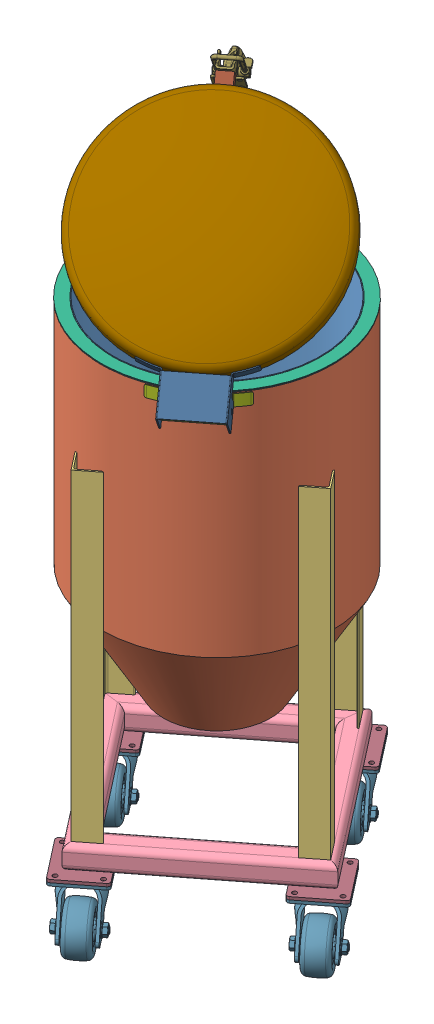
SolidWorks assembly Full Assembly, configuration Default. Lengths in mm.
Overall size (807.2 1692.42 807.2).
22 component instances, 14 part files, 40 mates.
Components (placement in the parent):
- Inner Tank (SUS304 Stainless)-1: Inner Tank (SUS304 Stainless) [Default] at origin size (460.38 751.55 460.38)
- Outer Tank (5052 Aluminum)-1: Outer Tank (5052 Aluminum) [Default] at (0 -53.975 0) size (510.43 744.74 510.43) (hidden)
- Legs^Full Assembly-1: Legs^Full Assembly [Default<As Machined>] at origin size (574.08 711.2 574.08) (virtual)
- Base Support^Full Assembly-1: Base Support^Full Assembly [Default<As Machined>] at origin size (609.73 50.8 609.73) (virtual)
- Part2^Full Assembly-1: Part2^Full Assembly [Default] at origin size (510.43 1.27 510.43) (virtual)
- Part1^Full Assembly-1: Part1^Full Assembly [Default] at origin size (511.18 1.59 511.18) (virtual)
- Aluminum Hinge Bottom-1: Aluminum Hinge Bottom [Default] at (181.4938 423.092 230.6241) x (0.788011 0 -0.615661) z (0.615661 0 0.788011) size (172.01 30.25 52.98)
- Aluminum Hinge Top-1: Aluminum Hinge Top [Default] at (181.4938 452.7347 230.6241) x (-0.788011 0 0.615661) z (0.615661 0 0.788011) size (104.78 30.94 44.15)
- Lid Assembly-1: Lid Assembly [Default] at (50.9024 635.7879 63.4747) x (-0.788011 0 0.615661) z (-0.464006 0.657251 -0.593901) size (548.2 438.64 642.51)
  - Lid-2: Lid [Default] at (211.2181 -60.2546 -11.3558) x (0.978448 -0.106422 -0.176957) z (0.118934 -0.410093 0.904256) size (467.18 231.16 437.78)
  - Stainless Hinge (Lid)-1: Stainless Hinge (Lid) [Default] at (0 31.628 -311.3405) x (-1 0 0) z (0 0 -1) size (198.67 69.73 99.8)
  - Part1-1: Part1 [Default] at origin size (30.23 25.4 22.84)
  - 5071A590-1: 5071A590 [Default] at (0.0381 -49.8475 255.0668) x (-1 0 0) z (0 1 0) size (60.86 76.1 227.53)
- 5071A590-1: 5071A590 [Default] at (-157.1255 407.035 -201.1115) x (0.788011 0 -0.615661) z (0 1 0) size (60.86 76.1 227.53)
- Caster Plate-1: Caster Plate [Default] at (36.7204 -517.525 -259.7516) x (0.614757 0 0.788716) z (-0.788716 0 0.614757) size (114.3 6.35 101.6)
- Caster Plate-3: Caster Plate [Default] at (-260.8562 -517.525 -27.8083) x (0.614757 0 0.788716) z (-0.788716 0 0.614757) size (114.3 6.35 101.6)
- Caster Plate-4: Caster Plate [Default] at (260.8562 -517.525 27.8083) x (0.614757 0 0.788716) z (-0.788716 0 0.614757) size (114.3 6.35 101.6)
- Caster Plate-5: Caster Plate [Default] at (-36.7204 -517.525 259.7516) x (0.614757 0 0.788716) z (-0.788716 0 0.614757) size (114.3 6.35 101.6)
- Caster Wheels-1: Caster Wheels [2531T25] at (64.0464 -609.6 -224.6931) x (-0.614757 0 -0.788716) z (0.788716 0 -0.614757) size (152.4 142.88 101.6)
- Caster Wheels-2: Caster Wheels [2531T25] at (-233.5302 -609.6 7.2501) x (-0.614757 0 -0.788716) z (0.788716 0 -0.614757) size (152.4 142.88 101.6)
- Caster Wheels-3: Caster Wheels [2531T25] at (-9.3944 -609.6 294.81) x (-0.614757 0 -0.788716) z (0.788716 0 -0.614757) size (152.4 142.88 101.6)
- Caster Wheels-4: Caster Wheels [2531T25] at (288.1822 -609.6 62.8668) x (-0.614757 0 -0.788716) z (0.788716 0 -0.614757) size (152.4 142.88 101.6)
Mates (geometry in assembly coordinates):
- Concentric1: concentric aligned: cylinder of Inner Tank (SUS304 Stainless)-1 through (0 457.2 0) axis (0 -1 0) radius 228.6; cylinder of Outer Tank (5052 Aluminum)-1 through (0 454.025 0) axis (0 -1 0) radius 254
- Distance1: distance = 3.175 mm aligned: plane of Inner Tank (SUS304 Stainless)-1 through (0 457.2 0) normal (0 1 0); plane of Outer Tank (5052 Aluminum)-1 through (0 454.025 0) normal (0 1 0)
- Concentric2: concentric anti-aligned: cylinder of Outer Tank (5052 Aluminum)-1 through (0 454.025 0) axis (0 -1 0) radius 255.2141; cylinder of Aluminum Hinge Bottom-1 through (0 401.9799 0) axis (0 1 0) radius 255.5875
- Parallel1: parallel aligned: plane of Legs^Full Assembly-1 through (287.0401 -460.375 35.5783) normal (0.788011 0 -0.615661); plane of Aluminum Hinge Bottom-1 through (181.4938 423.092 230.6241) normal (0.788011 0 -0.615661)
- Parallel2: parallel anti-aligned: plane of Aluminum Hinge Bottom-1 through (181.4938 423.092 230.6241) normal (0 1 0); plane of Aluminum Hinge Top-1 through (181.4938 452.7347 230.6241) normal (0 -1 0)
- Coincident3: coincident anti-aligned: plane of Aluminum Hinge Bottom-1 through (181.4938 423.092 230.6241) normal (0.788011 0 -0.615661); plane of Aluminum Hinge Top-1
- Coincident4: coincident aligned: plane of Aluminum Hinge Bottom-1 through (181.4938 421.8016 230.6241) normal (0.615661 0 0.788011); plane of Aluminum Hinge Top-1 through (181.4938 454.025 230.6241) normal (0.615661 0 0.788011)
- Coincident5: coincident anti-aligned: plane of Aluminum Hinge Bottom-1 through (181.4938 423.092 230.6241) normal (0 1 0); plane of Aluminum Hinge Top-1 through (222.7757 423.092 198.3711) normal (0 -1 0)
- Coincident6: coincident aligned: plane of Outer Tank (5052 Aluminum)-1 through (0 454.025 0) normal (0 1 0); plane of Aluminum Hinge Top-1 through (181.4938 454.025 230.6241) normal (0 1 0)
- Concentric3: concentric aligned: cylinder of Aluminum Hinge Top-1 through (131.4131 437.824 251.6203) axis (0.788011 0 -0.615661) radius 6.35; cylinder of Lid Assembly-1/Stainless Hinge (Lid)-1 through (94.4431 437.824 280.5044) axis (0.788011 0 -0.615661) radius 6.35
- Width1: width anti-aligned: plane of Lid Assembly-1/Stainless Hinge (Lid)-1 through (274.2942 495.265 257.6591) normal (0.788011 0 -0.615661); plane of Lid Assembly-1/Stainless Hinge (Lid)-1 through (185.2753 495.265 327.2082) normal (-0.788011 0 0.615661); plane of Aluminum Hinge Bottom-1 through (138.9609 369.5033 263.8544) normal (-0.788011 0 0.615661); plane of Aluminum Hinge Bottom-1 through (224.0267 369.5033 197.3937) normal (0.788011 0 -0.615661)
- LimitAngle1: limit planar angle = 0.717166 rad aligned: plane of assembly through (0 0 0) normal (0 1 0); plane of Lid Assembly-1/Part1-1
- Parallel3: parallel anti-aligned: plane of Legs^Full Assembly-1 through (-247.0091 -460.375 -66.8539) normal (-0.615661 0 -0.788011); plane of 5071A590-1 through (-178.3419 437.261 -184.5354) normal (0.615661 0 0.788011)
- Coincident7: coincident anti-aligned: plane of Part2^Full Assembly-1 through (0 455.295 0) normal (0 1 0); plane of 5071A590-1 through (-157.6415 455.295 -201.772) normal (0 -1 0)
- Tangent1: tangent anti-aligned: cylinder of Outer Tank (5052 Aluminum)-1 through (0 454.025 0) axis (0 -1 0) radius 255.2141; plane of 5071A590-1 through (-178.3419 437.261 -184.5354) normal (0.615661 0 0.788011)
- Coincident8: coincident: plane of 5071A590-1; point of assembly
- Coincident9: coincident anti-aligned: plane of Base Support^Full Assembly-1 through (51.1931 -511.175 -267.0067) normal (0 -1 0); plane of Caster Plate-1 through (36.7204 -511.175 -259.7516) normal (0 1 0)
- Distance2: distance = 22.225 mm aligned: plane of Caster Plate-1 through (41.6538 -511.175 -336.0564) normal (-0.614757 0 -0.788716); plane of Base Support^Full Assembly-1 through (27.7709 -473.075 -297.0568) normal (-0.614757 0 -0.788716)
- Distance3: distance = 22.225 mm aligned: plane of Caster Plate-1 through (111.9206 -511.175 -245.9061) normal (0.788716 0 -0.614757); plane of Base Support^Full Assembly-1 through (297.0568 -473.075 27.7709) normal (0.788716 0 -0.614757)
- Coincident13: coincident anti-aligned: plane of Base Support^Full Assembly-1 through (51.1931 -511.175 -267.0067) normal (0 -1 0); plane of Caster Plate-3 through (-260.8562 -511.175 -27.8083) normal (0 1 0)
- Distance5: distance = 22.225 mm aligned: plane of Caster Plate-3 through (-255.9228 -511.175 -104.1132) normal (-0.614757 0 -0.788716); plane of Base Support^Full Assembly-1 through (27.7709 -473.075 -297.0568) normal (-0.614757 0 -0.788716)
- Distance8: distance = 28.575 mm aligned: plane of Caster Plate-3 through (-185.656 -511.175 -13.9629) normal (0.788716 0 -0.614757); plane of Base Support^Full Assembly-1 through (-256.99 -498.475 -59.0005) normal (0.788716 0 -0.614757)
- Coincident14: coincident anti-aligned: plane of Base Support^Full Assembly-1 through (-51.1931 -511.175 267.0067) normal (0 -1 0); plane of Caster Plate-4 through (260.8562 -511.175 27.8083) normal (0 1 0)
- Distance9: distance = 22.225 mm aligned: plane of Caster Plate-4 through (336.0564 -511.175 41.6538) normal (0.614757 0 0.788716); plane of Base Support^Full Assembly-1 through (-27.7709 -473.075 297.0568) normal (0.614757 0 0.788716)
- Distance10: distance = 22.225 mm aligned: plane of Caster Plate-4 through (336.0564 -511.175 41.6538) normal (0.788716 0 -0.614757); plane of Base Support^Full Assembly-1 through (297.0568 -473.075 27.7709) normal (0.788716 0 -0.614757)
- Coincident17: coincident anti-aligned: plane of Base Support^Full Assembly-1 through (-267.0067 -511.175 -51.1931) normal (0 -1 0); plane of Caster Plate-5 through (-36.7204 -511.175 259.7516) normal (0 1 0)
- Distance11: distance = 22.225 mm aligned: plane of Caster Plate-5 through (38.4798 -511.175 273.597) normal (0.614757 0 0.788716); plane of Base Support^Full Assembly-1 through (-27.7709 -473.075 297.0568) normal (0.614757 0 0.788716)
- Distance12: distance = 22.225 mm aligned: plane of Base Support^Full Assembly-1 through (-297.0568 -473.075 -27.7709) normal (-0.788716 0 0.614757); plane of Caster Plate-5 through (-41.6538 -511.175 336.0564) normal (-0.788716 0 0.614757)
- Coincident20: coincident anti-aligned: plane of Caster Plate-1 through (36.7204 -517.525 -259.7516) normal (0 -1 0); plane of Caster Wheels-1 through (111.9206 -517.525 -245.9061) normal (0 1 0)
- Coincident23: coincident aligned: plane of Caster Plate-1 through (41.6538 -511.175 -336.0564) normal (-0.614757 0 -0.788716); plane of Caster Wheels-1 through (41.6538 -517.525 -336.0564) normal (-0.614757 0 -0.788716)
- Coincident24: coincident aligned: plane of Caster Plate-1 through (111.9206 -511.175 -245.9061) normal (0.788716 0 -0.614757); plane of Caster Wheels-1 through (111.9206 -523.875 -245.9061) normal (0.788716 0 -0.614757)
- Coincident25: coincident anti-aligned: plane of Caster Plate-3 through (-260.8562 -517.525 -27.8083) normal (0 -1 0); plane of Caster Wheels-2 through (-185.656 -517.525 -13.9629) normal (0 1 0)
- Coincident26: coincident aligned: plane of Caster Plate-3 through (-265.7896 -511.175 48.4965) normal (-0.788716 0 0.614757); plane of Caster Wheels-2 through (-265.7896 -523.875 48.4965) normal (-0.788716 0 0.614757)
- Coincident27: coincident aligned: plane of Caster Plate-3 through (-255.9228 -511.175 -104.1132) normal (-0.614757 0 -0.788716); plane of Caster Wheels-2 through (-255.9228 -517.525 -104.1132) normal (-0.614757 0 -0.788716)
- Coincident28: coincident anti-aligned: plane of Caster Plate-5 through (-36.7204 -517.525 259.7516) normal (0 -1 0); plane of Caster Wheels-3 through (38.4798 -517.525 273.597) normal (0 1 0)
- Coincident29: coincident aligned: plane of Caster Plate-5 through (38.4798 -511.175 273.597) normal (0.614757 0 0.788716); plane of Caster Wheels-3 through (38.4798 -517.525 273.597) normal (0.614757 0 0.788716)
- Coincident30: coincident aligned: plane of Caster Plate-5 through (-41.6538 -511.175 336.0564) normal (-0.788716 0 0.614757); plane of Caster Wheels-3 through (-41.6538 -523.875 336.0564) normal (-0.788716 0 0.614757)
- Coincident31: coincident anti-aligned: plane of Caster Plate-4 through (260.8562 -517.525 27.8083) normal (0 -1 0); plane of Caster Wheels-4 through (336.0564 -517.525 41.6538) normal (0 1 0)
- Coincident32: coincident aligned: plane of Caster Plate-4 through (336.0564 -511.175 41.6538) normal (0.788716 0 -0.614757); plane of Caster Wheels-4 through (336.0564 -523.875 41.6538) normal (0.788716 0 -0.614757)
- Coincident33: coincident aligned: plane of Caster Plate-4 through (336.0564 -511.175 41.6538) normal (0.614757 0 0.788716); plane of Caster Wheels-4 through (336.0564 -517.525 41.6538) normal (0.614757 0 0.788716)
